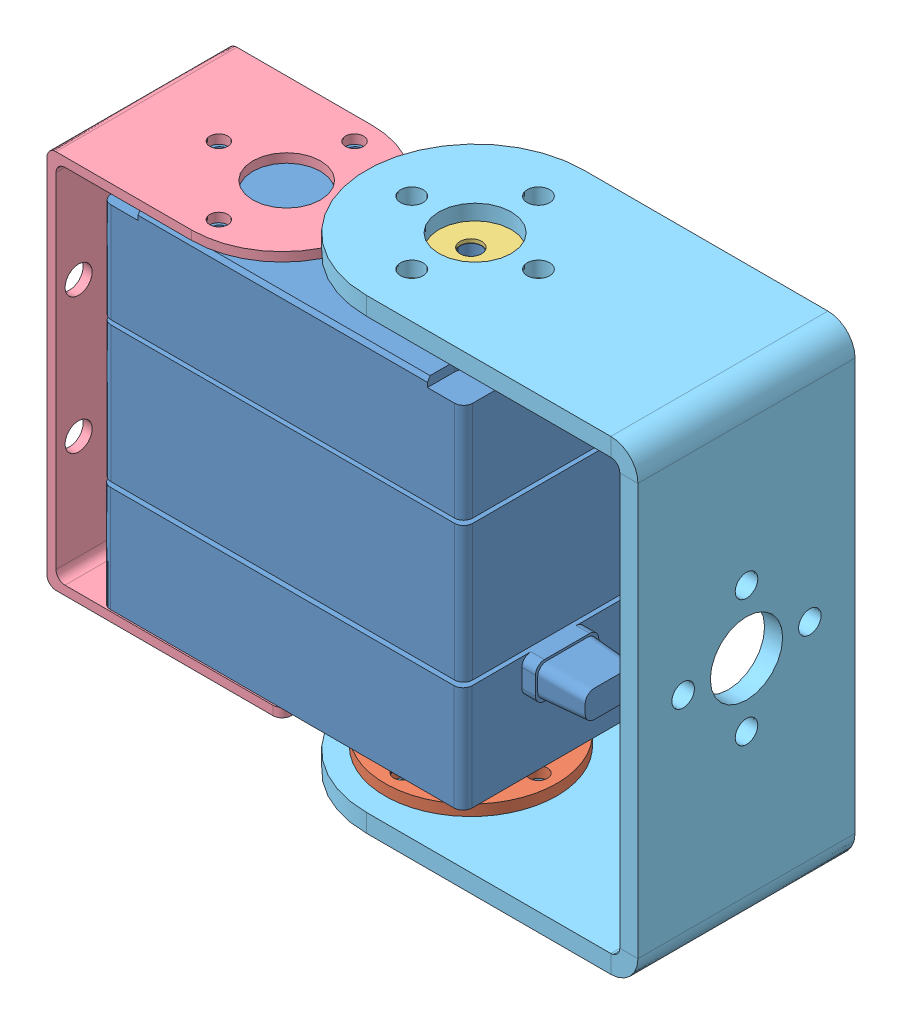
SolidWorks assembly Assembly, configuration Default. Lengths in mm.
Overall size (67.3 51.5 26.87).
5 component instances, 5 part files, 7 mates.
Components (placement in the parent):
- dual shaft servo-1: dual shaft servo [Predeterminado] at (14.992 2.8195 38.2318) size (46.51 48.8 20.07)
- accessory 1-1: accessory 1 [Predeterminado] at (35.7217 1.0691 58.2951) x (0.70399 0 0.71021) z (0.71021 0 -0.70399) size (19 2.2 19)
- accessory 2-2: accessory 2 [Predeterminado] at (7.8921 46.4181 29.4135) x (-0.683613 0 -0.729844) z (0.729844 0 -0.683613) size (19 3.2 19)
- support 1 ( dimensions check)-1: support 1 ( dimensions check) [Predeterminado] at (-9.1537 29.6478 38.798) x (0 1 0) z (0 0 -1) size (42 26 20)
- U Bracket-1: U Bracket [Défaut] at (58.1419 23.5615 38.2647) x (0 -1 0) z (0 0 -1) size (51.5 42 24)
Mates (geometry in assembly coordinates):
- Concentric14: concentric anti-aligned: circle of dual shaft servo-1; circle of accessory 1-1
- Concentric16: concentric aligned: circle of dual shaft servo-1; circle of accessory 2-2
- Parallel6: parallel anti-aligned: plane of dual shaft servo-1 through (-3.158 30.3195 28.2318) normal (-1 0 0); plane of support 1 ( dimensions check)-1 through (-8.1537 29.6478 38.798) normal (1 0 0)
- Concentric21: concentric anti-aligned: circle of dual shaft servo-1; circle of support 1 ( dimensions check)-1
- Concentric22: concentric anti-aligned: circle of dual shaft servo-1; circle of support 1 ( dimensions check)-1
- Parallel7: parallel anti-aligned: plane of dual shaft servo-1 through (36.842 30.3195 38.2318) normal (1 0 0); plane of U Bracket-1 through (56.1419 49.3115 26.2647) normal (-1 0 0)
- Concentric24: concentric anti-aligned: circle of accessory 1-1; circle of U Bracket-1
